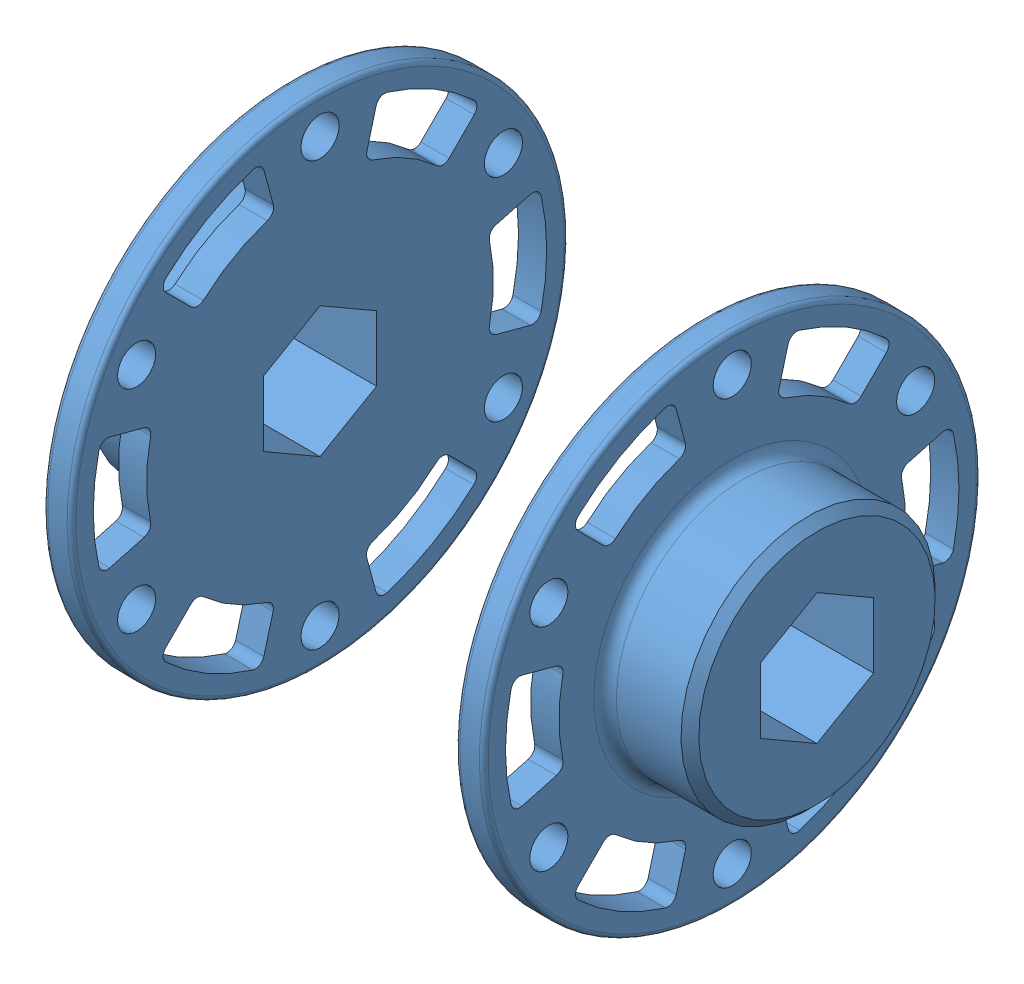
SolidWorks assembly 2018-202-A-Right, configuration Default. Lengths in mm.
Overall size (68.58 76.33 76.33).
3 component instances, 2 part files, 9 mates.
Components (placement in the parent):
- 2018-200-D017-Right-1: 2018-200-D017-Right [Default] x (0 -1 0) z (0 0 1) (suppressed, hidden)
- 2018-200-D005-1: 2018-200-D005 [Default] at (34.2942 0.0396 -0.0405) x (-1 0 0) z (0 -0.866025 -0.5) size (12.7 55.88 55.88)
- 2018-200-D005-2: 2018-200-D005 [Default] at (-34.2858 0.0396 -0.0405) size (12.7 55.88 55.88)
Mates (geometry in assembly coordinates):
- Coincident1: coincident: plane of 2018-200-D017-Right-1 through (0 0 0) normal (0 -1 0); plane of assembly through (0 0 0) normal (0 1 0)
- Coincident2: coincident: plane of 2018-200-D017-Right-1 through (0 0 0) normal (1 0 0); plane of assembly through (0 0 0) normal (1 0 0)
- Coincident3: coincident: plane of 2018-200-D017-Right-1 through (0 0 0) normal (0 0 1); plane of assembly through (0 0 0) normal (0 0 1)
- Coincident4: coincident: plane of 2018-200-D017-Right-1 through (-21.5858 0.0396 -0.0405) normal (-1 0 0); plane of 2018-200-D005-2 through (-21.5858 31.5864 -0.0405) normal (1 0 0)
- Concentric1: concentric: cylinder of 2018-200-D017-Right-1 through (-18.4108 11.9459 -20.6627) axis (-1 0 0) radius 2.1526; cylinder of 2018-200-D005-2 through (-107.3791 11.9459 -20.6627) axis (1 0 0) radius 2.15
- Concentric2: concentric: cylinder of 2018-200-D017-Right-1 through (-18.4108 23.8521 -0.0405) axis (-1 0 0) radius 2.1526; cylinder of 2018-200-D005-2 through (-107.3791 23.8521 -0.0405) axis (1 0 0) radius 2.15
- Coincident5: coincident: plane of 2018-200-D017-Right-1 through (21.5942 0.0396 -0.0405) normal (1 0 0); plane of 2018-200-D005-1 through (21.5942 15.813 -27.3608) normal (-1 0 0)
- Concentric3: concentric: cylinder of 2018-200-D017-Right-1 through (18.4192 23.8521 -0.0405) axis (1 0 0) radius 2.1526; cylinder of 2018-200-D005-1 through (107.3876 23.8521 -0.0405) axis (-1 0 0) radius 2.15
- Concentric4: concentric: cylinder of 2018-200-D017-Right-1 through (18.4192 11.9459 -20.6627) axis (1 0 0) radius 2.1526; cylinder of 2018-200-D005-1 through (107.3876 11.9459 -20.6627) axis (-1 0 0) radius 2.15
